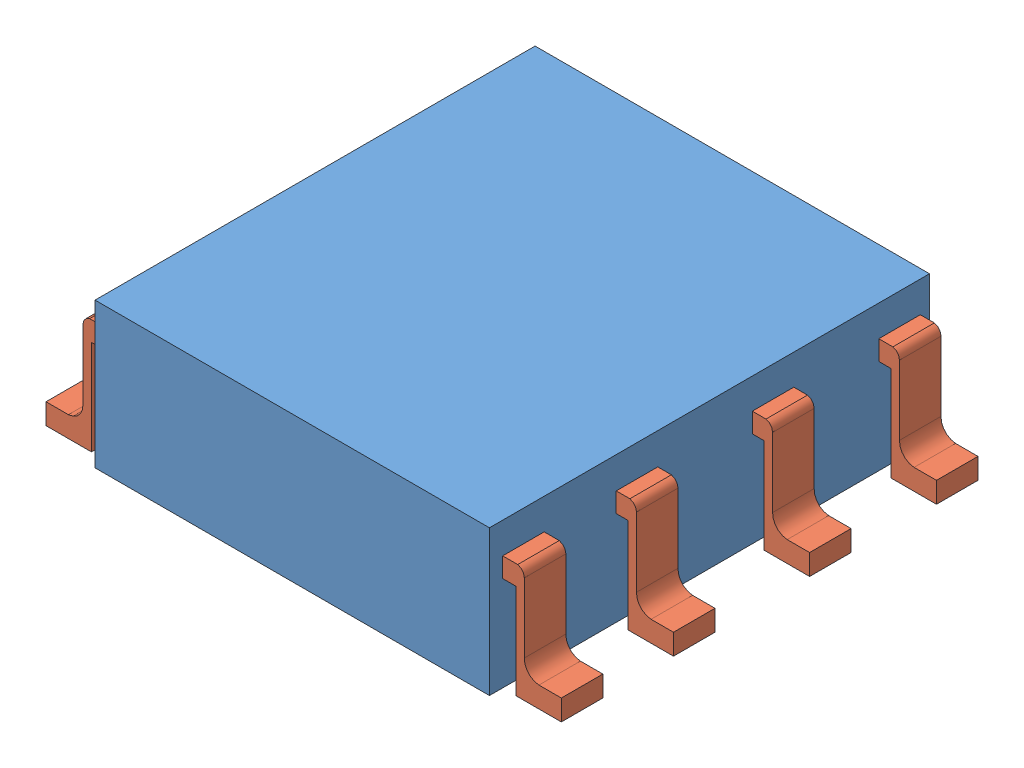
SolidWorks assembly CI, configuration Default. Lengths in mm.
Overall size (4.95 1.41 4.24).
9 component instances, 2 part files, 0 mates.
Components (placement in the parent):
- block CI-1: block CI [Default] at (4.2864 1.8173 3.9842) size (3.8 1.4 4.24)
- pin CI-2: pin CI [Default] at (3.305 3.0561 4.8321) x (1 0 0) z (0 -1 0) size (0.66 0.4 1.1)
- pin CI-3: pin CI [Default] at (3.2915 3.0512 3.7381) x (1 0 0) z (0 -1 0) size (0.66 0.4 1.1)
- pin CI-4: pin CI [Default] at (3.2959 3.0561 1.2085) x (1 0 0) z (0 -1 0) size (0.66 0.4 1.1)
- pin CI-5: pin CI [Default] at (3.292 3.061 2.427) x (1 0 0) z (0 -1 0) size (0.66 0.4 1.1)
- pin CI-7: pin CI [Default] at (-0.8863 3.047 3.9568) x (-1 0 0) z (0 -1 0) size (0.66 0.4 1.1)
- pin CI-8: pin CI [Default] at (-0.8872 3.0608 5.2472) x (-1 0 0) z (0 -1 0) size (0.66 0.4 1.1)
- pin CI-9: pin CI [Default] at (-0.8896 3.0513 1.5769) x (-1 0 0) z (0 -1 0) size (0.66 0.4 1.1)
- pin CI-10: pin CI [Default] at (-0.8872 3.0513 2.618) x (-1 0 0) z (0 -1 0) size (0.66 0.4 1.1)
